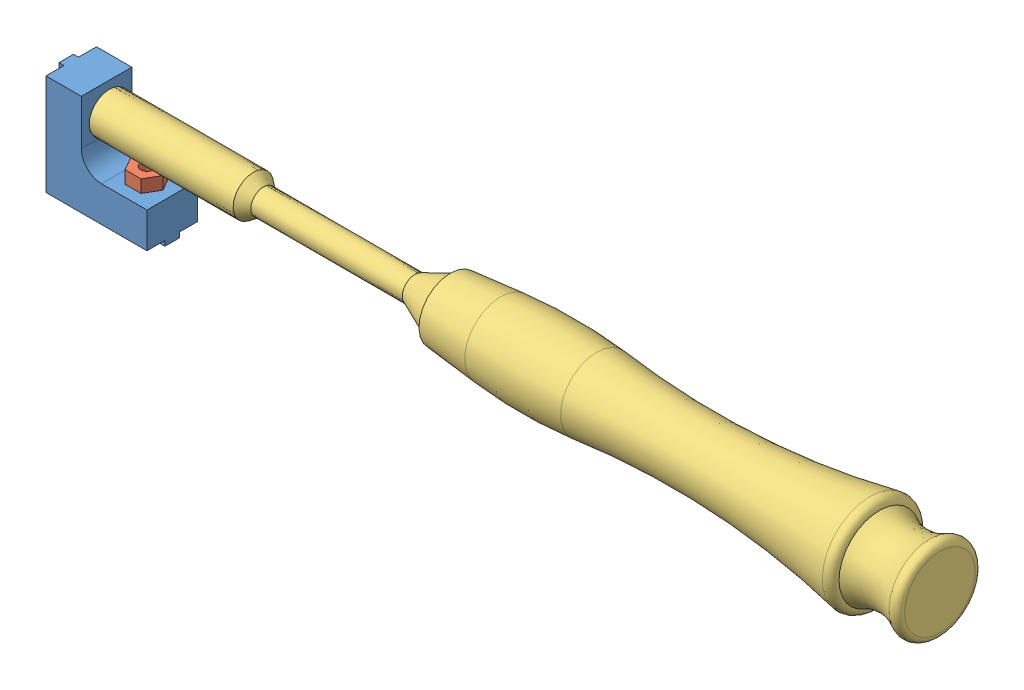
SolidWorks assembly Bracket_L_20x20_WithNuts, configuration Default. Lengths in mm.
Overall size (173.06 28.91 25.81).
4 component instances, 3 part files, 5 mates.
Components (placement in the parent):
- Bracket_L_Big_20x20-1: Bracket_L_Big_20x20 [Default] at (-14.1333 3.6014 16.2451) size (21 21 10)
- Nut3mm-1: Nut3mm [Default] at (-4.6333 18.6014 21.2451) x (0 0 1) z (-1 0 0) size (6.35 5.5 2.5)
- Nut3mm-2: Nut3mm [Default] at (0.8667 13.1014 21.2451) x (1 0 0) z (0 -1 0) size (6.35 5.5 2.5)
- Screw-Driver-5.5_CR-V-2: Screw-Driver-5.5_CR-V [Default] at (-6.5754 18.6014 21.2451) x (1 0 0) z (0 0.47325 0.880928) size (164.5 19.06 19.06)
Mates (geometry in assembly coordinates):
- Concentric1: concentric anti-aligned: cylinder of Bracket_L_Big_20x20-1 through (5.8667 18.6014 21.2451) axis (-1 0 0) radius 1.5; cylinder of Nut3mm-1 through (-7.1333 18.6014 21.2451) axis (1 0 0) radius 1.25
- Coincident1: coincident anti-aligned: plane of Bracket_L_Big_20x20-1 through (-7.1333 14.6014 26.2451) normal (1 0 0); plane of Nut3mm-1 through (-7.1333 18.6014 21.2451) normal (-1 0 0)
- Concentric2: concentric anti-aligned: cylinder of Bracket_L_Big_20x20-1 through (0.8667 23.6014 21.2451) axis (0 -1 0) radius 1.5; cylinder of Nut3mm-2 through (0.8667 10.6014 21.2451) axis (0 1 0) radius 1.25
- Coincident3: coincident anti-aligned: plane of Bracket_L_Big_20x20-1 through (5.8667 10.6014 26.2451) normal (0 1 0); plane of Nut3mm-2 through (0.8667 10.6014 21.2451) normal (0 -1 0)
- Concentric3: concentric anti-aligned: cylinder of Nut3mm-1 through (-7.1333 18.6014 21.2451) axis (1 0 0) radius 1.25; cylinder of Screw-Driver-5.5_CR-V-2 through (17.4246 18.6014 21.2451) axis (-1 0 0) radius 2.5
